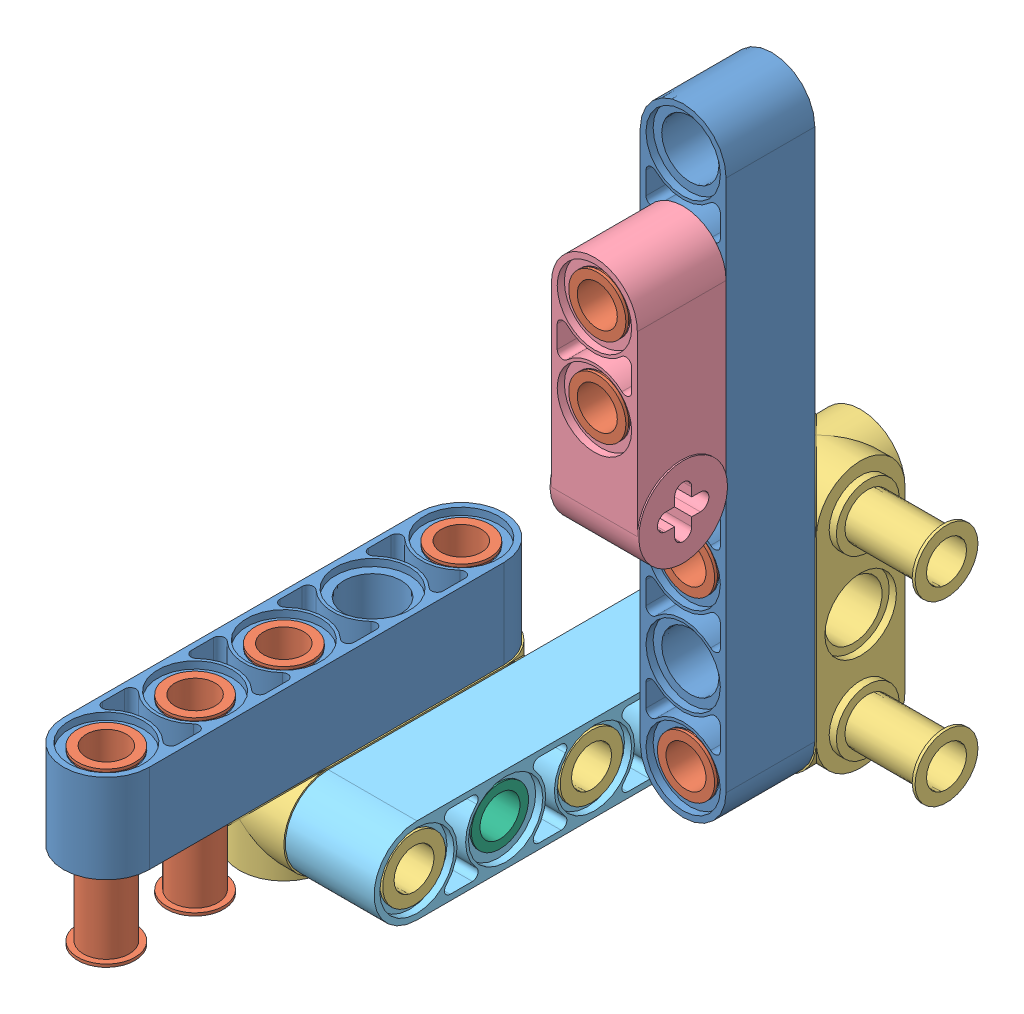
SolidWorks assembly left_rider_bottom, configuration Default. Lengths in mm.
Overall size (39.12 54.99 54.99).
16 component instances, 6 part files, 48 mates.
Components (placement in the parent):
- All_Straight-1: All_Straight [Seven] x (0 1 0) z (0 0 1) size (54.86 7.62 7.87)
- BlackConnectorSmall-1: BlackConnectorSmall [Default] at (0 0 15.494) x (0 0 -1) z (1 0 0) size (15.24 5.59 5.59)
- BlackConnectorSmall-3: BlackConnectorSmall [Default] at (0 -7.874 15.494) x (0 0 -1) z (1 0 0) size (15.24 5.59 5.59)
- BlackConnectorSmall-4: BlackConnectorSmall [Default] at (0 -23.622 -7.62) x (0 0 1) z (1 0 0) size (15.24 5.59 5.59)
- BlackConnectorSmall-5: BlackConnectorSmall [Default] at (0 -39.37 -7.62) x (0 0 1) z (1 0 0) size (15.24 5.59 5.59)
- Light_Gray_X1-1: Light_Gray_X1 [Default] at (3.937 -31.496 -3.937) x (0 1 0) z (0 0 1) size (23.62 23.11 7.87)
- StraightTurn_Twohole_1Cross-1: StraightTurn_Twohole_1Cross [Default] at (3.81 -7.747 11.811) x (0 -1 0) z (-1 0 0) size (23.5 7.87 7.87)
- L_Three_Five_90degrees-1: L_Three_Five_90degrees [Default] at (-11.557 -39.37 3.937) x (0 0 -1) z (1 0 0) size (39.12 23.37 7.87)
- Light_Gray_X1-2: Light_Gray_X1 [Default] at (-19.685 -39.37 19.685) x (0 0 -1) z (0 -1 0) size (23.62 23.11 7.87)
- BlueConnectorLong-1: BlueConnectorLong [Default] at (-27.305 -39.37 19.685) size (22.86 5.59 5.59)
- BlackConnectorSmall-6: BlackConnectorSmall [Default] at (-15.748 -27.813 11.811) x (0 -1 0) z (0 0 1) size (15.24 5.59 5.59)
- BlackConnectorSmall-7: BlackConnectorSmall [Default] at (-15.748 -27.813 27.559) x (0 -1 0) z (0 0 1) size (15.24 5.59 5.59)
- All_Straight-2: All_Straight [Five] at (-15.748 -35.433 19.685) x (0 0 -1) z (0 1 0) size (39.12 7.62 7.87)
- All_Straight-3: All_Straight [Three] at (-27.559 -39.37 19.685) x (0 0 -1) z (1 0 0) size (23.37 7.62 7.87)
- BlackConnectorSmall-8: BlackConnectorSmall [Default] at (-15.748 -43.053 35.433) x (0 1 0) z (0 0 1) size (15.24 5.59 5.59)
- BlackConnectorSmall-9: BlackConnectorSmall [Default] at (-15.748 -43.053 43.307) x (0 1 0) z (1 0 0) size (15.24 5.59 5.59)
Mates (geometry in assembly coordinates):
- Coincident1: coincident aligned: plane of All_Straight-1; plane of assembly through (0 0 0) normal (0 1 0)
- Coincident2: coincident anti-aligned: plane of All_Straight-1; plane of assembly through (0 0 0) normal (1 0 0)
- Coincident3: coincident aligned: plane of All_Straight-1 through (0 0 0) normal (0 0 1); plane of assembly through (0 0 0) normal (0 0 1)
- Concentric1: concentric anti-aligned: cylinder of All_Straight-1 through (0 0 3.937) axis (0 0 -1) radius 2.54; cylinder of BlackConnectorSmall-1 through (0 0 15.494) axis (0 0 1) radius 2.032
- Coincident4: coincident anti-aligned: plane of All_Straight-1 through (0 0 7.239) normal (0 0 1); plane of BlackConnectorSmall-1 through (0 2.032 7.239) normal (0 0 -1)
- Coincident5: coincident aligned: plane of BlackConnectorSmall-1 through (0 0 15.494) normal (1 0 0); plane of assembly through (0 0 0) normal (1 0 0)
- Concentric3: concentric anti-aligned: cylinder of All_Straight-1 through (0 -7.874 3.937) axis (0 0 -1) radius 2.54; cylinder of BlackConnectorSmall-3 through (0 -7.874 15.494) axis (0 0 1) radius 2.032
- Coincident7: coincident anti-aligned: plane of All_Straight-1 through (0 -7.874 7.239) normal (0 0 1); plane of BlackConnectorSmall-3 through (0 -5.842 7.239) normal (0 0 -1)
- Coincident8: coincident aligned: plane of BlackConnectorSmall-3 through (0 -7.874 15.494) normal (1 0 0); plane of assembly through (0 0 0) normal (1 0 0)
- Concentric4: concentric aligned: cylinder of All_Straight-1 through (0 -23.622 3.937) axis (0 0 -1) radius 2.54; cylinder of BlackConnectorSmall-4 through (0 -23.622 -7.62) axis (0 0 -1) radius 2.032
- Coincident9: coincident anti-aligned: plane of All_Straight-1 through (0 -23.622 0.635) normal (0 0 -1); plane of BlackConnectorSmall-4 through (0 -25.654 0.635) normal (0 0 1)
- Coincident10: coincident aligned: plane of BlackConnectorSmall-4 through (0 -23.622 -7.62) normal (1 0 0); plane of assembly through (0 0 0) normal (1 0 0)
- Concentric8: concentric aligned: cylinder of All_Straight-1 through (0 -39.37 3.937) axis (0 0 -1) radius 2.54; cylinder of BlackConnectorSmall-5 through (0 -39.37 -7.62) axis (0 0 -1) radius 2.032
- Coincident13: coincident anti-aligned: plane of All_Straight-1 through (0 -39.37 0.635) normal (0 0 -1); plane of BlackConnectorSmall-5 through (0 -41.402 0.635) normal (0 0 1)
- Coincident14: coincident aligned: plane of BlackConnectorSmall-5 through (0 -39.37 -7.62) normal (1 0 0); plane of assembly through (0 0 0) normal (1 0 0)
- Concentric10: concentric anti-aligned: cylinder of BlackConnectorSmall-4 through (0 -23.622 -7.62) axis (0 0 -1) radius 2.032; cylinder of Light_Gray_X1-1 through (0 -23.622 -7.874) axis (0 0 1) radius 2.286
- Concentric11: concentric anti-aligned: cylinder of BlackConnectorSmall-5 through (0 -39.37 -7.62) axis (0 0 -1) radius 2.032; cylinder of Light_Gray_X1-1 through (0 -39.37 -7.874) axis (0 0 1) radius 2.286
- Coincident16: coincident anti-aligned: plane of BlackConnectorSmall-4 through (0 -26.416 -0.635) normal (0 0 -1); plane of Light_Gray_X1-1 through (0 -23.622 -0.635) normal (0 0 1)
- Concentric12: concentric anti-aligned: cylinder of BlackConnectorSmall-1 through (0 0 15.494) axis (0 0 1) radius 2.032; cylinder of StraightTurn_Twohole_1Cross-1 through (0 0 11.811) axis (0 0 -1) radius 2.54
- Concentric13: concentric anti-aligned: cylinder of BlackConnectorSmall-3 through (0 -7.874 15.494) axis (0 0 1) radius 2.032; cylinder of StraightTurn_Twohole_1Cross-1 through (0 -7.874 11.811) axis (0 0 -1) radius 2.54
- Coincident17: coincident anti-aligned: plane of BlackConnectorSmall-1 through (0 2.794 8.509) normal (0 0 1); plane of StraightTurn_Twohole_1Cross-1 through (0 0 8.509) normal (0 0 -1)
- Concentric14: concentric anti-aligned: cylinder of Light_Gray_X1-1 through (-11.557 -23.622 -3.937) axis (1 0 0) radius 2.032; cylinder of L_Three_Five_90degrees-1 through (-7.747 -23.622 -3.937) axis (-1 0 0) radius 2.54
- Concentric15: concentric anti-aligned: cylinder of Light_Gray_X1-1 through (-11.557 -39.37 -3.937) axis (1 0 0) radius 2.032; cylinder of L_Three_Five_90degrees-1 through (-7.747 -39.37 -3.937) axis (-1 0 0) radius 2.54
- Coincident18: coincident anti-aligned: plane of Light_Gray_X1-1 through (-4.572 -23.622 -3.937) normal (-1 0 0); plane of L_Three_Five_90degrees-1 through (-4.572 -23.622 -3.937) normal (1 0 0)
- Concentric18: concentric anti-aligned: cylinder of Light_Gray_X1-2 through (-15.748 -35.433 11.811) axis (0 -1 0) radius 2.286; cylinder of BlackConnectorSmall-6 through (-15.748 -27.813 11.811) axis (0 1 0) radius 2.032
- Coincident20: coincident anti-aligned: plane of Light_Gray_X1-2 through (-15.748 -36.068 11.811) normal (0 1 0); plane of BlackConnectorSmall-6 through (-13.716 -36.068 11.811) normal (0 -1 0)
- Parallel1: parallel aligned: plane of BlackConnectorSmall-6 through (-15.748 -27.813 11.811) normal (0 0 1); plane of assembly through (0 0 0) normal (0 0 1)
- Concentric19: concentric anti-aligned: cylinder of Light_Gray_X1-2 through (-15.748 -35.433 27.559) axis (0 -1 0) radius 2.286; cylinder of BlackConnectorSmall-7 through (-15.748 -27.813 27.559) axis (0 1 0) radius 2.032
- Coincident22: coincident anti-aligned: plane of Light_Gray_X1-2 through (-15.748 -36.068 27.559) normal (0 1 0); plane of BlackConnectorSmall-7 through (-13.716 -36.068 27.559) normal (0 -1 0)
- Parallel2: parallel aligned: plane of BlackConnectorSmall-7 through (-15.748 -27.813 27.559) normal (0 0 1); plane of assembly through (0 0 0) normal (0 0 1)
- Concentric20: concentric anti-aligned: cylinder of BlackConnectorSmall-6 through (-15.748 -27.813 11.811) axis (0 1 0) radius 2.032; cylinder of All_Straight-2 through (-15.748 -31.496 11.811) axis (0 -1 0) radius 2.54
- Concentric21: concentric anti-aligned: cylinder of BlackConnectorSmall-7 through (-15.748 -27.813 27.559) axis (0 1 0) radius 2.032; cylinder of All_Straight-2 through (-15.748 -31.496 27.559) axis (0 -1 0) radius 2.54
- Coincident24: coincident anti-aligned: plane of BlackConnectorSmall-6 through (-12.954 -34.798 11.811) normal (0 1 0); plane of All_Straight-2 through (-15.748 -34.798 11.811) normal (0 -1 0)
- Concentric22: concentric anti-aligned: cylinder of Light_Gray_X1-2 through (-19.304 -39.37 19.685) axis (1 0 0) radius 2.54; cylinder of BlueConnectorLong-1 through (-27.305 -39.37 19.685) axis (-1 0 0) radius 2.032
- Coincident25: coincident anti-aligned: plane of Light_Gray_X1-2 through (-19.05 -39.37 19.685) normal (-1 0 0); plane of BlueConnectorLong-1 through (-19.05 -37.338 19.685) normal (1 0 0)
- Parallel3: parallel aligned: plane of BlueConnectorLong-1 through (-27.305 -39.37 19.685) normal (0 1 0); plane of assembly through (0 0 0) normal (0 1 0)
- Concentric23: concentric aligned: cylinder of All_Straight-2 through (-15.748 -31.496 35.433) axis (0 -1 0) radius 2.54; cylinder of BlackConnectorSmall-8 through (-15.748 -43.053 35.433) axis (0 -1 0) radius 2.032
- Coincident27: coincident anti-aligned: plane of All_Straight-2 through (-15.748 -34.798 35.433) normal (0 -1 0); plane of BlackConnectorSmall-8 through (-17.78 -34.798 35.433) normal (0 1 0)
- Concentric24: concentric aligned: cylinder of All_Straight-2 through (-15.748 -31.496 43.307) axis (0 -1 0) radius 2.54; cylinder of BlackConnectorSmall-9 through (-15.748 -43.053 43.307) axis (0 -1 0) radius 2.032
- Coincident28: coincident anti-aligned: plane of All_Straight-2 through (-15.748 -34.798 43.307) normal (0 -1 0); plane of BlackConnectorSmall-9 through (-15.748 -34.798 45.339) normal (0 1 0)
- Parallel4: parallel aligned: plane of BlackConnectorSmall-8 through (-15.748 -43.053 35.433) normal (0 0 1); plane of assembly through (0 0 0) normal (0 0 1)
- Parallel5: parallel aligned: plane of BlackConnectorSmall-9; plane of assembly through (0 0 0) normal (0 0 1)
- Concentric25: concentric anti-aligned: cylinder of Light_Gray_X1-2 through (-27.305 -39.37 11.811) axis (1 0 0) radius 2.032; cylinder of All_Straight-3 through (-23.622 -39.37 11.811) axis (-1 0 0) radius 2.54
- Concentric26: concentric anti-aligned: cylinder of Light_Gray_X1-2 through (-27.305 -39.37 27.559) axis (1 0 0) radius 2.032; cylinder of All_Straight-3 through (-23.622 -39.37 27.559) axis (-1 0 0) radius 2.54
- Coincident31: coincident anti-aligned: plane of Light_Gray_X1-2 through (-20.32 -39.37 27.559) normal (-1 0 0); plane of All_Straight-3 through (-20.32 -39.37 27.559) normal (1 0 0)
- Concentric27: concentric aligned: cylinder of L_Three_Five_90degrees-1 through (-7.747 -39.37 11.811) axis (-1 0 0) radius 2.54; cylinder of Light_Gray_X1-2 through (-4.191 -39.37 11.811) axis (-1 0 0) radius 2.032
- Concentric28: concentric aligned: cylinder of L_Three_Five_90degrees-1 through (-7.747 -39.37 27.559) axis (-1 0 0) radius 2.54; cylinder of Light_Gray_X1-2 through (-4.191 -39.37 27.559) axis (-1 0 0) radius 2.032
- Coincident32: coincident anti-aligned: plane of L_Three_Five_90degrees-1 through (-11.176 -39.37 11.811) normal (-1 0 0); plane of Light_Gray_X1-2 through (-11.176 -39.37 11.811) normal (1 0 0)
